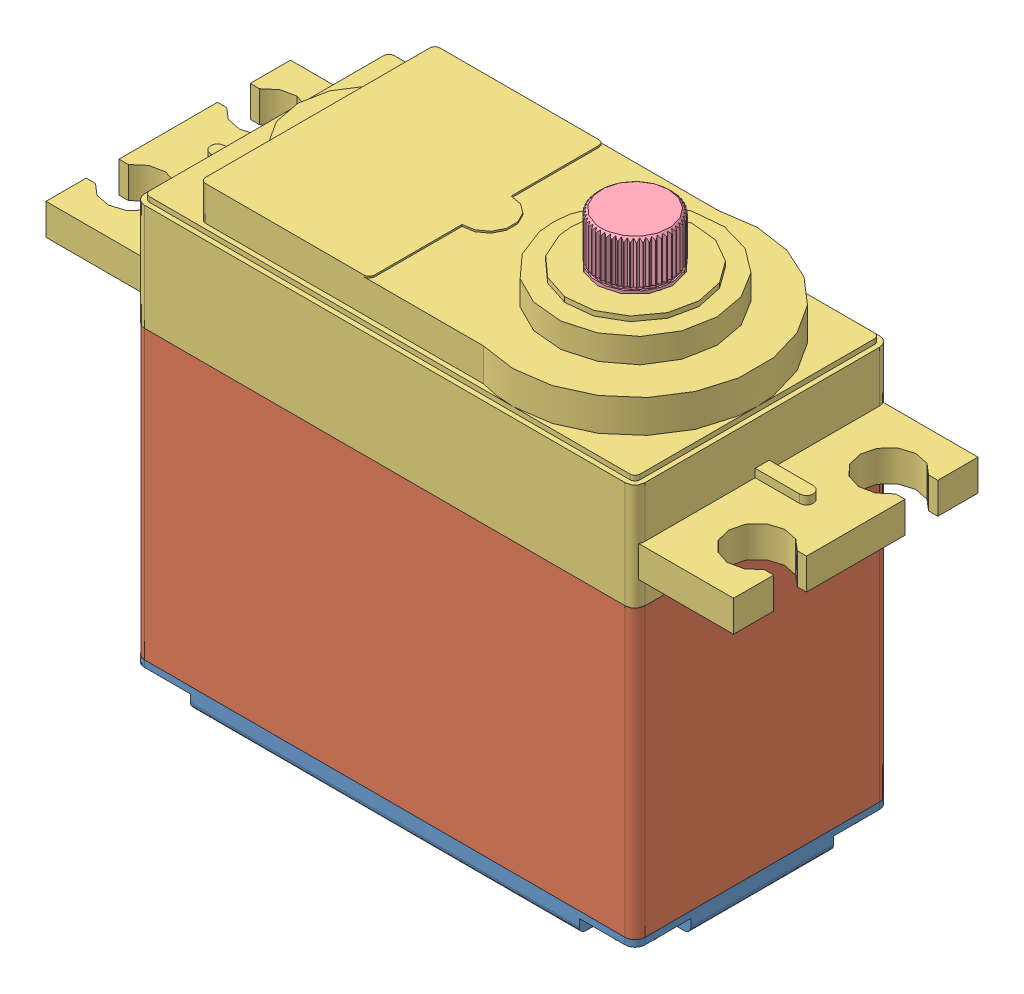
SolidWorks assembly servo, configuration Default. Lengths in mm.
Overall size (53.21 40.96 20.14).
8 component instances, 5 part files, 16 mates.
Components (placement in the parent):
- bottom cover-1: bottom cover [Default] at (-1.1028 -6.6399 5.093) size (38.73 2.86 19.69)
- servo Case-1: servo Case [Default] at (-1.1028 15.982 5.093) size (38.73 27.58 19.69)
- servo cover-1: servo cover [Default] at (18.2647 17.1726 -4.7495) x (-1 0 0) z (0 1 0) size (53.21 19.69 13.46)
- spline output-1: spline output [Default] at (8.4222 20.6778 5.093) size (16.97 15.24 16.97)
- long screw-1: long screw [CR-BHMS 0.06-80x0.625x0.625-S] at (16.2327 -6.3732 -2.7175) x (0 1 0) z (0.998694 0 -0.051099) size (31.27 3.2 3.2)
- long screw-2: long screw [CR-BHMS 0.06-80x0.625x0.625-S] at (-18.4383 -6.3732 -2.7175) x (0 1 0) z (0.768793 0 -0.639497) size (31.27 3.2 3.2)
- long screw-3: long screw [CR-BHMS 0.06-80x0.625x0.625-S] at (-18.4383 -6.3732 12.9035) x (0 1 0) z (0.201227 0 0.979545) size (31.27 3.2 3.2)
- long screw-4: long screw [CR-BHMS 0.06-80x0.625x0.625-S] at (16.2327 -6.3732 12.9035) x (0 1 0) z (0.729133 0 0.684372) size (31.27 3.2 3.2)
Mates (geometry in assembly coordinates):
- Concentric1: concentric: cylinder of servo Case-1 through (8.4222 21.6176 5.093) axis (0 -1 0) radius 3; cylinder of spline output-1 through (8.4222 20.6778 5.093) axis (0 -1 0) radius 5
- Coincident1: coincident: plane of servo Case-1 through (8.4222 21.6176 5.093) normal (0 1 0); plane of spline output-1 through (8.4222 21.6176 5.093) normal (0 -1 0)
- Concentric2: concentric: circle of servo Case-1; circle of servo cover-1
- Concentric3: concentric: circle of servo cover-1; cylinder of spline output-1 through (8.4222 20.6778 5.093) axis (0 -1 0) radius 3.4925
- Coincident2: coincident: plane of servo Case-1 through (-19.7083 17.1726 14.1735) normal (0 1 0); plane of servo cover-1 through (-19.7083 17.1726 14.1735) normal (0 -1 0)
- Concentric4: concentric: cylinder of bottom cover-1 through (-18.4383 -5.0524 -2.7175) axis (0 -1 0) radius 0.7937; cylinder of servo Case-1 through (-18.4383 -9.0486 -2.7175) axis (0 1 0) radius 0.7937
- Concentric5: concentric: cylinder of bottom cover-1 through (-18.4383 -5.0524 12.9035) axis (0 -1 0) radius 0.7937; cylinder of servo Case-1 through (-18.4383 -9.0486 12.9035) axis (0 1 0) radius 0.7937
- Coincident3: coincident: plane of bottom cover-1 through (-19.7083 -5.0524 14.1735) normal (0 1 0); plane of servo Case-1 through (-19.7083 -5.0524 14.1735) normal (0 -1 0)
- Concentric6: concentric: cylinder of servo Case-1 through (16.2327 -9.0486 -2.7175) axis (0 1 0) radius 0.7937; cylinder of long screw-1 through (16.2327 -31.7732 -2.7175) axis (0 -1 0) radius 0.762
- Concentric7: concentric: cylinder of servo Case-1 through (-18.4383 -9.0486 -2.7175) axis (0 1 0) radius 0.7937; cylinder of long screw-2 through (-18.4383 -31.7732 -2.7175) axis (0 -1 0) radius 0.762
- Concentric8: concentric: cylinder of servo Case-1 through (-18.4383 -9.0486 12.9035) axis (0 1 0) radius 0.7937; cylinder of long screw-3 through (-18.4383 -31.7732 12.9035) axis (0 -1 0) radius 0.762
- Concentric9: concentric: cylinder of servo Case-1 through (16.2327 -9.0486 12.9035) axis (0 1 0) radius 0.7937; cylinder of long screw-4 through (16.2327 -31.7732 12.9035) axis (0 -1 0) radius 0.762
- Coincident4: coincident: plane of bottom cover-1 through (-19.7083 -5.5604 14.1735) normal (0 -1 0); plane of long screw-4 through (15.7112 -5.5604 13.4591) normal (0 1 0)
- Coincident5: coincident: plane of bottom cover-1 through (-19.7083 -5.5604 14.1735) normal (0 -1 0); plane of long screw-3 through (-19.1847 -5.5604 13.0568) normal (0 1 0)
- Coincident6: coincident: plane of bottom cover-1 through (-19.7083 -5.5604 14.1735) normal (0 -1 0); plane of long screw-1 through (16.2716 -5.5604 -1.9565) normal (0 1 0)
- Coincident7: coincident: plane of bottom cover-1 through (-19.7083 -5.5604 14.1735) normal (0 -1 0); plane of long screw-2 through (-17.951 -5.5604 -2.1317) normal (0 1 0)
